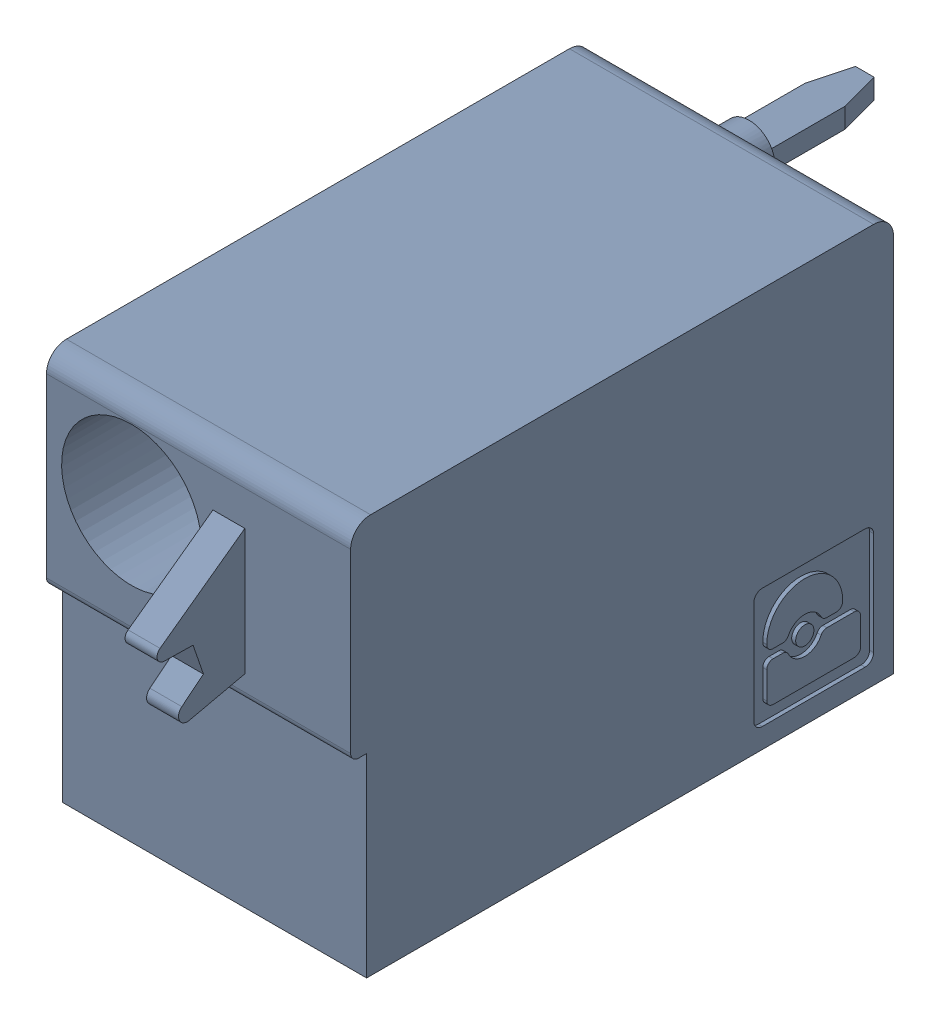
SolidWorks assembly J41, configuration Default. Lengths in mm.
Overall size (7.62 10 19.2).
2 component instances, 1 part files, 0 mates.
Components (placement in the parent):
- 1790487-1: 1790487 [Default] at (109.625 -5.67 -10.6) x (0 1 0) z (1 0 0) size (10 19.2 7.62)
  - ffkdsa1-v2-7.62-1: ffkdsa1-v2-7.62 [Default] at (-15.6914 -27.508 9.12) x (0 -1 0) z (0 0 1) size (19.2 10 7.62)
